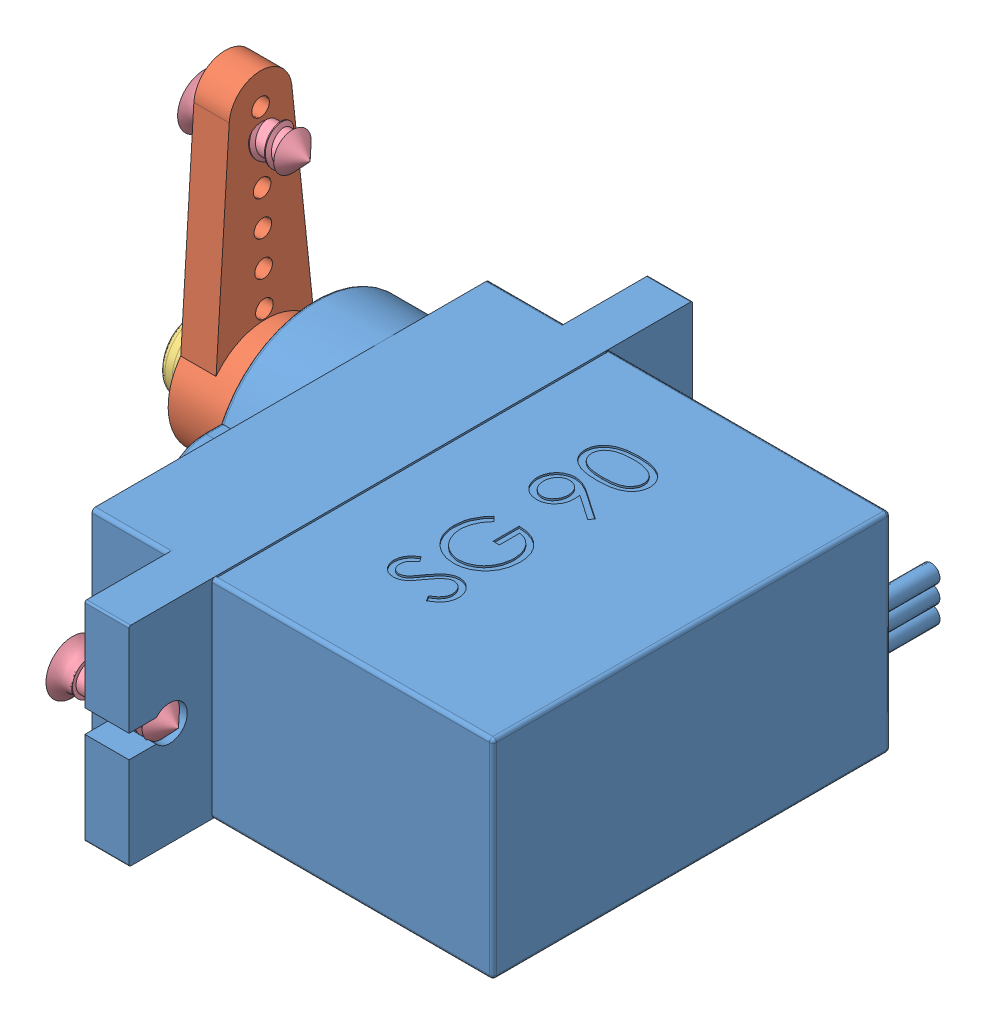
SolidWorks assembly AR1, configuration Predeterminado. Lengths in mm.
Overall size (34.06 21.84 31.9).
6 component instances, 4 part files, 19 mates.
Components (placement in the parent):
- sg90-2: sg90 [Default] at (126.818 -193.0635 98.9775) x (0 0 1) z (0 -1 0) size (31.9 29.9 11.8)
- SG90 plastic Horn-2: SG90 plastic Horn [Default] at (97.368 -198.9635 104.8775) x (0 0.999767 0.021606) z (0 -0.021606 0.999767) size (19.4 4 7.07)
- (M2_3_mm)_90116A007_METRIC 316 SS PAN HEAD PHILLIPS MACHINE SCREW-2: (M2_3_mm)_90116A007_METRIC 316 SS PAN HEAD PHILLIPS MACHINE SCREW [90116A007] at (97.368 -198.9635 104.8775) x (0 0 1) z (-1 0 0) size (4 4 4.68)
- M2x6 SelfTap Screw-1: M2x6 SelfTap Screw [Predeterminado] at (93.868 -186.4635 104.8775) x (0 0.924225 0.381849) z (-1 0 0) size (3.4 3.28 6)
- M2x6 SelfTap Screw-3: M2x6 SelfTap Screw [Predeterminado] at (105.418 -198.9635 123.8775) x (0 0.924225 0.381849) z (-1 0 0) size (3.4 3.28 6)
- M2x6 SelfTap Screw-5: M2x6 SelfTap Screw [Predeterminado] at (105.418 -198.9635 96.5775) x (0 0.924225 0.381849) z (-1 0 0) size (3.4 3.28 6)
Mates (geometry in assembly coordinates):
- Coincidente272: coincident: plane of ? through (205.2764 -198.9635 104.8775) normal (1 0 0); plane of ? through (205.2764 -197.7187 104.8985) normal (-1 0 0)
- Concéntrica139: concentric: circle of ?; circle of ?
- Concéntrica154: concentric: circle of ?; circle of ?
- Distancia47: distance = 1 mm: plane of ? through (194.7764 -198.9635 96.5775) normal (1 0 0); plane of ? through (193.7764 -204.8635 94.2775) normal (1 0 0)
- Concéntrica155: concentric: circle of ?; circle of ?
- Distancia48: distance = 1 mm: plane of ? through (194.7764 -198.9635 123.8775) normal (1 0 0); plane of ? through (193.7764 -193.0635 126.1775) normal (1 0 0)
- Coincidente273: coincident: plane of sg90-2 through (96.918 -198.9635 104.8775) normal (-1 0 0); plane of SG90 plastic Horn-2 through (96.918 -197.7188 104.9044) normal (1 0 0)
- Concéntrica140: concentric: circle of sg90-2; circle of SG90 plastic Horn-2
- Concéntrica156: concentric: circle of sg90-2; circle of M2x6 SelfTap Screw-5
- Distancia49: distance = 3 mm: plane of M2x6 SelfTap Screw-5 through (105.418 -198.9635 96.5775) normal (-1 0 0); plane of sg90-2 through (108.418 -193.0635 94.2775) normal (-1 0 0)
- Concéntrica158: concentric: circle of sg90-2; circle of M2x6 SelfTap Screw-3
- Distancia50: distance = 3 mm: plane of M2x6 SelfTap Screw-3 through (105.418 -198.9635 123.8775) normal (-1 0 0); plane of sg90-2 through (108.418 -204.8635 126.1775) normal (-1 0 0)
- Coincidente275: coincident: plane of ? through (206.8264 -195.429 104.9372) normal (1 0 0); plane of ? through (206.8264 -158.9009 101.2558) normal (-1 0 0)
- Concéntrica143: concentric: circle of ?; circle of ?
- Bloquear1: lock: unknown of ?; unknown of ?
- Coincidente281: coincident: plane of ? through (207.8264 -158.9009 101.2558) normal (1 0 0); plane of ? through (207.8264 -198.9635 104.8775) normal (-1 0 0)
- Concéntrica145: concentric: circle of ?; circle of ?
- Concéntrica148: concentric: circle of ?; circle of ?
- Distancia46: distance = 0.5 mm: plane of ? through (208.3264 -186.4635 104.8775) normal (1 0 0); plane of ? through (207.8264 -158.9009 101.2558) normal (1 0 0)
